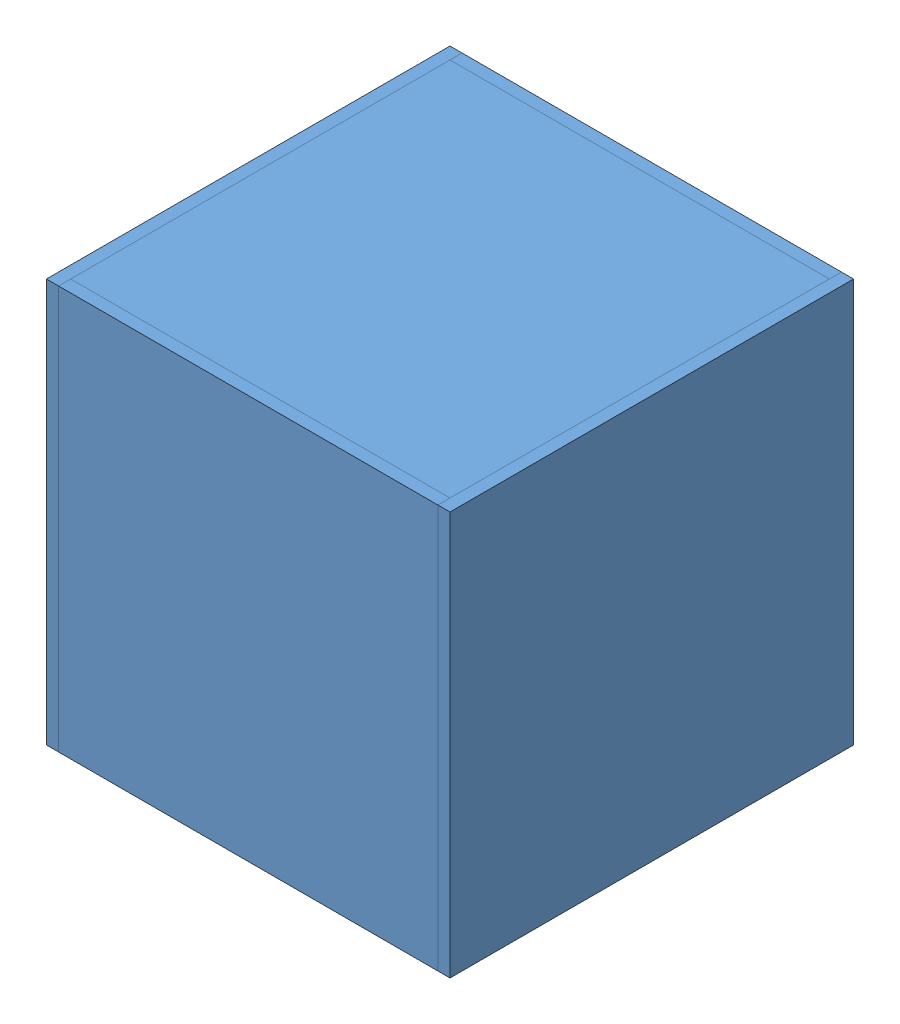
SolidWorks assembly Configurations Cube Assembly, configuration Default. Lengths in mm.
Overall size (100 102.84 100).
19 component instances, 4 part files, 42 mates.
Components (placement in the parent):
- Configurations Cube-1: Configurations Cube [Bottom] at (28.9682 53.4278 79.3064) size (94 3 94)
- 25x.5 Aluminum Hex Female Female Standoff-1: 25x.5 Aluminum Hex Female Female Standoff [Default] at (59.3682 62.7778 111.2064) x (-0.495409 0 -0.86866) z (0 -1 0) size (6.35 8.06 12.7)
- 25x.5 Aluminum Hex Female Female Standoff-2: 25x.5 Aluminum Hex Female Female Standoff [Default] at (6.9682 62.7778 116.3064) x (-0.010984 0 0.99994) z (0 -1 0) size (6.35 8.06 12.7)
- 25x.5 Aluminum Hex Female Female Standoff-3: 25x.5 Aluminum Hex Female Female Standoff [Default] at (59.3682 62.7778 83.3064) x (0.110199 0 0.99391) z (0 -1 0) size (6.35 8.06 12.7)
- 25x.5 Aluminum Hex Female Female Standoff-4: 25x.5 Aluminum Hex Female Female Standoff [Default] at (8.5682 62.7778 68.0064) x (0.924181 0 0.381955) z (0 -1 0) size (6.35 8.06 12.7)
- ArduinoUno-1: ArduinoUno [Default] at (25.9682 69.1278 92.1564) size (74.8 12.1 53.3)
- socket head cap screw_ai-2: socket head cap screw_ai [HX-SHCS 0.112-40x0.25x0.25-N] at (59.3682 73.5726 111.2064) x (0 -1 0) z (-0.992907 0 -0.11889) size (9.19 4.65 4.65)
- socket head cap screw_ai-4: socket head cap screw_ai [HX-SHCS 0.112-40x0.25x0.25-N] at (59.3682 73.5726 83.3064) x (0 -1 0) z (0.232953 0 0.972488) size (9.19 4.65 4.65)
- socket head cap screw_ai-5: socket head cap screw_ai [HX-SHCS 0.112-40x0.25x0.25-N] at (8.5682 73.5726 68.0064) x (0 -1 0) z (0.344039 0 -0.938955) size (9.19 4.65 4.65)
- socket head cap screw_ai-6: socket head cap screw_ai [HX-SHCS 0.112-40x0.25x0.25-N] at (6.9682 73.5726 116.3064) x (0 -1 0) z (-0.833226 0 0.552933) size (9.19 4.65 4.65)
- socket head cap screw_ai-7: socket head cap screw_ai [HX-SHCS 0.112-40x0.25x0.25-N] at (6.9682 50.583 116.3064) x (0 1 0) z (0.50143 0 -0.865198) size (9.19 4.65 4.65)
- socket head cap screw_ai-8: socket head cap screw_ai [HX-SHCS 0.112-40x0.25x0.25-N] at (59.3682 50.583 111.2064) x (0 1 0) z (-0.963331 0 0.268315) size (9.19 4.65 4.65)
- socket head cap screw_ai-10: socket head cap screw_ai [HX-SHCS 0.112-40x0.25x0.25-N] at (8.5682 50.583 68.0064) x (0 1 0) z (0.899528 0 -0.436864) size (9.19 4.65 4.65)
- Configurations Cube-2: Configurations Cube [USB] at (-21.0318 103.4278 79.3064) x (0 -1 0) z (0 0 1) size (100 3 100)
- Configurations Cube-3: Configurations Cube [Front Back] at (75.9682 103.4278 79.3064) x (0 -1 0) z (0 0 1) size (100 3 100)
- Configurations Cube-4: Configurations Cube [Left Right] at (28.9682 103.4278 129.3064) x (1 0 0) z (0 1 0) size (94 3 100)
- Configurations Cube-6: Configurations Cube [Top] at (28.9682 150.4278 79.3064) size (94 3 94)
- Configurations Cube-7: Configurations Cube [Left Right] at (28.9682 103.4278 32.3064) x (1 0 0) z (0 1 0) size (94 3 100)
- socket head cap screw_ai-11: socket head cap screw_ai [HX-SHCS 0.112-40x0.25x0.25-N] at (59.3682 50.583 83.3064) x (0 1 0) z (0.977304 0 0.21184) size (9.19 4.65 4.65)
Mates (geometry in assembly coordinates):
- Coincident1: coincident anti-aligned: plane of Configurations Cube-1 through (28.9682 56.4278 79.3064) normal (0 1 0); plane of 25x.5 Aluminum Hex Female Female Standoff-4 through (8.5682 56.4278 68.0064) normal (0 -1 0)
- Coincident2: coincident anti-aligned: plane of Configurations Cube-1 through (28.9682 56.4278 79.3064) normal (0 1 0); plane of 25x.5 Aluminum Hex Female Female Standoff-2 through (6.9682 56.4278 116.3064) normal (0 -1 0)
- Coincident3: coincident anti-aligned: plane of Configurations Cube-1 through (28.9682 56.4278 79.3064) normal (0 1 0); plane of 25x.5 Aluminum Hex Female Female Standoff-3 through (59.3682 56.4278 83.3064) normal (0 -1 0)
- Coincident4: coincident anti-aligned: plane of Configurations Cube-1 through (28.9682 56.4278 79.3064) normal (0 1 0); plane of 25x.5 Aluminum Hex Female Female Standoff-1 through (59.3682 56.4278 111.2064) normal (0 -1 0)
- Coincident5: coincident anti-aligned: plane of 25x.5 Aluminum Hex Female Female Standoff-4 through (8.5682 69.1278 68.0064) normal (0 1 0); plane of ArduinoUno-1 through (58.9682 69.1278 65.5064) normal (0 -1 0)
- Concentric6: concentric anti-aligned: circle of 25x.5 Aluminum Hex Female Female Standoff-1; circle of ArduinoUno-1
- Concentric8: concentric anti-aligned: cylinder of ArduinoUno-1 through (59.3682 70.7278 111.2064) axis (0 -1 0) radius 1.6; cylinder of socket head cap screw_ai-2 through (59.3682 105.3226 111.2064) axis (0 1 0) radius 2.3241
- Coincident7: coincident anti-aligned: plane of ArduinoUno-1 through (58.9682 70.7278 65.5064) normal (0 1 0); plane of socket head cap screw_ai-2 through (59.0919 70.7278 113.514) normal (0 -1 0)
- Concentric101: concentric anti-aligned: cylinder of ArduinoUno-1 through (59.3682 70.7278 83.3064) axis (0 -1 0) radius 1.6; cylinder of socket head cap screw_ai-4 through (59.3682 105.3226 83.3064) axis (0 1 0) radius 2.3241
- Coincident91: coincident anti-aligned: plane of ArduinoUno-1 through (58.9682 70.7278 65.5064) normal (0 1 0); plane of socket head cap screw_ai-4 through (61.6284 70.7278 82.765) normal (0 -1 0)
- Concentric111: concentric anti-aligned: cylinder of ArduinoUno-1 through (8.5682 70.7278 68.0064) axis (0 -1 0) radius 1.6; cylinder of socket head cap screw_ai-5 through (8.5682 105.3226 68.0064) axis (0 1 0) radius 2.3241
- Coincident101: coincident anti-aligned: plane of ArduinoUno-1 through (58.9682 70.7278 65.5064) normal (0 1 0); plane of socket head cap screw_ai-5 through (6.386 70.7278 67.2068) normal (0 -1 0)
- Concentric121: concentric anti-aligned: cylinder of ArduinoUno-1 through (6.9682 70.7278 116.3064) axis (0 -1 0) radius 1.6; cylinder of socket head cap screw_ai-6 through (6.9682 105.3226 116.3064) axis (0 1 0) radius 2.3241
- Coincident111: coincident anti-aligned: plane of ArduinoUno-1 through (58.9682 70.7278 65.5064) normal (0 1 0); plane of socket head cap screw_ai-6 through (8.2533 70.7278 118.2429) normal (0 -1 0)
- Coincident121: coincident anti-aligned: plane of Configurations Cube-1 through (28.9682 53.4278 79.3064) normal (0 -1 0); plane of socket head cap screw_ai-7 through (8.979 53.4278 117.4718) normal (0 1 0)
- Coincident131: coincident anti-aligned: plane of Configurations Cube-1 through (28.9682 53.4278 79.3064) normal (0 -1 0); plane of socket head cap screw_ai-8 through (58.7446 53.4278 108.9676) normal (0 1 0)
- Coincident151: coincident anti-aligned: plane of Configurations Cube-1 through (28.9682 53.4278 79.3064) normal (0 -1 0); plane of socket head cap screw_ai-10 through (9.5835 53.4278 70.097) normal (0 1 0)
- Coincident16: coincident anti-aligned: plane of Configurations Cube-1 through (-18.0318 56.4278 126.3064) normal (-1 0 0); plane of Configurations Cube-2 through (-18.0318 103.4278 79.3064) normal (1 0 0)
- Coincident17: coincident aligned: plane of Configurations Cube-1 through (28.9682 53.4278 79.3064) normal (0 -1 0); plane of Configurations Cube-2 through (-18.0318 53.4278 129.3064) normal (0 -1 0)
- Coincident18: coincident anti-aligned: plane of Configurations Cube-1 through (-18.0318 56.4278 126.3064) normal (0 0 1); plane of Configurations Cube-4 through (28.9682 103.4278 126.3064) normal (0 0 -1)
- Coincident19: coincident aligned: plane of Configurations Cube-1 through (28.9682 53.4278 79.3064) normal (0 -1 0); plane of Configurations Cube-4 through (-18.0318 53.4278 126.3064) normal (0 -1 0)
- Coincident20: coincident anti-aligned: plane of Configurations Cube-2 through (-18.0318 103.4278 79.3064) normal (1 0 0); plane of Configurations Cube-4 through (-18.0318 153.4278 126.3064) normal (-1 0 0)
- Coincident21: coincident aligned: plane of Configurations Cube-2 through (-18.0318 153.4278 129.3064) normal (0 0 1); plane of Configurations Cube-4 through (28.9682 103.4278 129.3064) normal (0 0 1)
- Coincident193: coincident anti-aligned: plane of Configurations Cube-2 through (-18.0318 103.4278 79.3064) normal (1 0 0); plane of Configurations Cube-6 through (-18.0318 153.4278 126.3064) normal (-1 0 0)
- Coincident194: coincident anti-aligned: plane of Configurations Cube-4 through (28.9682 103.4278 126.3064) normal (0 0 -1); plane of Configurations Cube-6 through (-18.0318 153.4278 126.3064) normal (0 0 1)
- Coincident196: coincident anti-aligned: plane of Configurations Cube-6 through (-18.0318 153.4278 32.3064) normal (0 0 -1); plane of Configurations Cube-7 through (28.9682 103.4278 32.3064) normal (0 0 1)
- Coincident197: coincident anti-aligned: plane of Configurations Cube-2 through (-18.0318 103.4278 79.3064) normal (1 0 0); plane of Configurations Cube-7 through (-18.0318 153.4278 29.3064) normal (-1 0 0)
- Coincident198: coincident: line of Configurations Cube-6 through (75.9682 153.4278 32.3064) axis (-1 0 0); plane of Configurations Cube-7 through (-18.0318 153.4278 29.3064) normal (0 1 0)
- Coincident201: coincident anti-aligned: plane of Configurations Cube-3 through (78.9682 53.4278 129.3064) normal (0 -1 0); line of Configurations Cube-1 through (75.9682 53.4278 126.3064) axis (0 0 -1)
- Coincident202: coincident anti-aligned: plane of Configurations Cube-3 through (75.9682 103.4278 79.3064) normal (-1 0 0); plane of Configurations Cube-6 through (75.9682 153.4278 126.3064) normal (1 0 0)
- Coincident203: coincident: plane of Configurations Cube-3 through (78.9682 153.4278 29.3064) normal (0 0 -1); line of Configurations Cube-7 through (75.9682 153.4278 29.3064) axis (0 -1 0)
- Concentric162: concentric anti-aligned: cylinder of Configurations Cube-1 through (59.3682 53.4278 111.2064) axis (0 1 0) radius 1.6; cylinder of socket head cap screw_ai-8 through (59.3682 18.833 111.2064) axis (0 -1 0) radius 1.4224
- Concentric163: concentric anti-aligned: cylinder of Configurations Cube-1 through (8.5682 53.4278 68.0064) axis (0 1 0) radius 1.6; cylinder of socket head cap screw_ai-10 through (8.5682 18.833 68.0064) axis (0 -1 0) radius 1.4224
- Concentric164: concentric anti-aligned: cylinder of Configurations Cube-1 through (6.9682 53.4278 116.3064) axis (0 1 0) radius 1.6; cylinder of socket head cap screw_ai-7 through (6.9682 18.833 116.3064) axis (0 -1 0) radius 1.4224
- Concentric1651: concentric anti-aligned: cylinder of Configurations Cube-1 through (59.3682 53.4278 83.3064) axis (0 1 0) radius 1.6; cylinder of socket head cap screw_ai-11 through (59.3682 18.833 83.3064) axis (0 -1 0) radius 2.3241
- Coincident2041: coincident anti-aligned: plane of Configurations Cube-1 through (28.9682 53.4278 79.3064) normal (0 -1 0); plane of socket head cap screw_ai-11 through (58.8759 53.4278 85.5778) normal (0 1 0)
- Concentric168: concentric aligned: cylinder of 25x.5 Aluminum Hex Female Female Standoff-3 through (59.3682 56.4278 83.3064) axis (0 -1 0) radius 1.0287; cylinder of socket head cap screw_ai-11 through (59.3682 18.833 83.3064) axis (0 -1 0) radius 1.4224
- Concentric169: concentric aligned: cylinder of 25x.5 Aluminum Hex Female Female Standoff-4 through (8.5682 56.4278 68.0064) axis (0 -1 0) radius 1.0287; cylinder of socket head cap screw_ai-10 through (8.5682 18.833 68.0064) axis (0 -1 0) radius 1.4224
- Concentric170: concentric aligned: cylinder of 25x.5 Aluminum Hex Female Female Standoff-2 through (6.9682 56.4278 116.3064) axis (0 -1 0) radius 1.0287; cylinder of socket head cap screw_ai-7 through (6.9682 18.833 116.3064) axis (0 -1 0) radius 1.4224
- Concentric171: concentric aligned: cylinder of 25x.5 Aluminum Hex Female Female Standoff-1 through (59.3682 56.4278 111.2064) axis (0 -1 0) radius 1.0287; cylinder of socket head cap screw_ai-8 through (59.3682 18.833 111.2064) axis (0 -1 0) radius 1.4224
- Concentric172: concentric anti-aligned: cylinder of 25x.5 Aluminum Hex Female Female Standoff-4 through (8.5682 56.4278 68.0064) axis (0 -1 0) radius 1.0287; cylinder of socket head cap screw_ai-5 through (8.5682 105.3226 68.0064) axis (0 1 0) radius 1.4224
- Coincident205: coincident: line of Configurations Cube-1 through (75.9682 53.4278 32.3064) axis (-1 0 0); plane of Configurations Cube-7 through (-18.0318 53.4278 29.3064) normal (0 -1 0)
